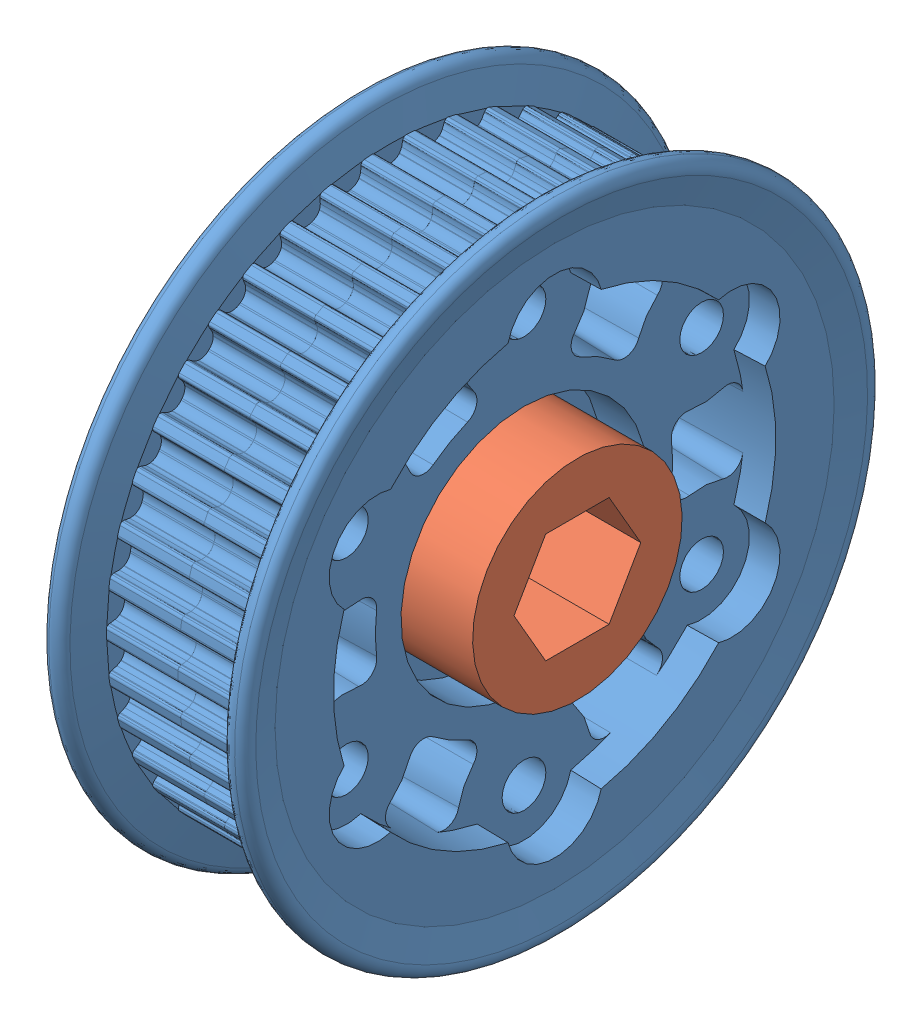
SolidWorks assembly 42 HTD Pulley 500 Hex Hub, configuration Default. Lengths in mm.
Overall size (25.4 78.07 78.07).
4 component instances, 2 part files, 3 mates.
Components (placement in the parent):
- 42 - 2014 tooth pulley assembly-1: 42 - 2014 tooth pulley assembly [Default] at (-12.8322 41.7203 71.9507) size (23.46 74.23 74.23)
  - 42 tooth HTD Pulley half 2014-1: 42 tooth HTD Pulley half 2014 [Default] at origin size (13 74.23 74.23)
  - 42 tooth HTD Pulley half 2014-2: 42 tooth HTD Pulley half 2014 [Default] at (16.6624 0 0) x (-1 0 0) z (0 0.000084 1) size (13 74.23 74.23)
- 500 Hex Hub-1: 500 Hex Hub [Default] at (1.2188 41.7203 71.9507) x (1 0 0) z (0 0.500018 0.866015) size (25.4 57.15 57.15)
Mates (geometry in assembly coordinates):
- Concentric1: concentric anti-aligned: cylinder of 42 - 2014 tooth pulley assembly-1/42 tooth HTD Pulley half 2014-2 through (-2.5833 41.7203 71.9507) axis (1 0 0) radius 14.2875; cylinder of 500 Hex Hub-1 through (9.0118 41.7203 71.9507) axis (-1 0 0) radius 12.1666
- Coincident1: coincident anti-aligned: plane of 42 - 2014 tooth pulley assembly-1/42 tooth HTD Pulley half 2014-1 through (-11.8162 41.7203 71.9507) normal (-1 0 0); circle of 500 Hex Hub-1
- Concentric2: concentric aligned: cylinder of 42 - 2014 tooth pulley assembly-1/42 tooth HTD Pulley half 2014-2 through (-4.501 53.6257 51.329) axis (1 0 0) radius 2.54; cylinder of 500 Hex Hub-1 through (-11.8162 53.6261 51.3283) axis (1 0 0) radius 2.5908
